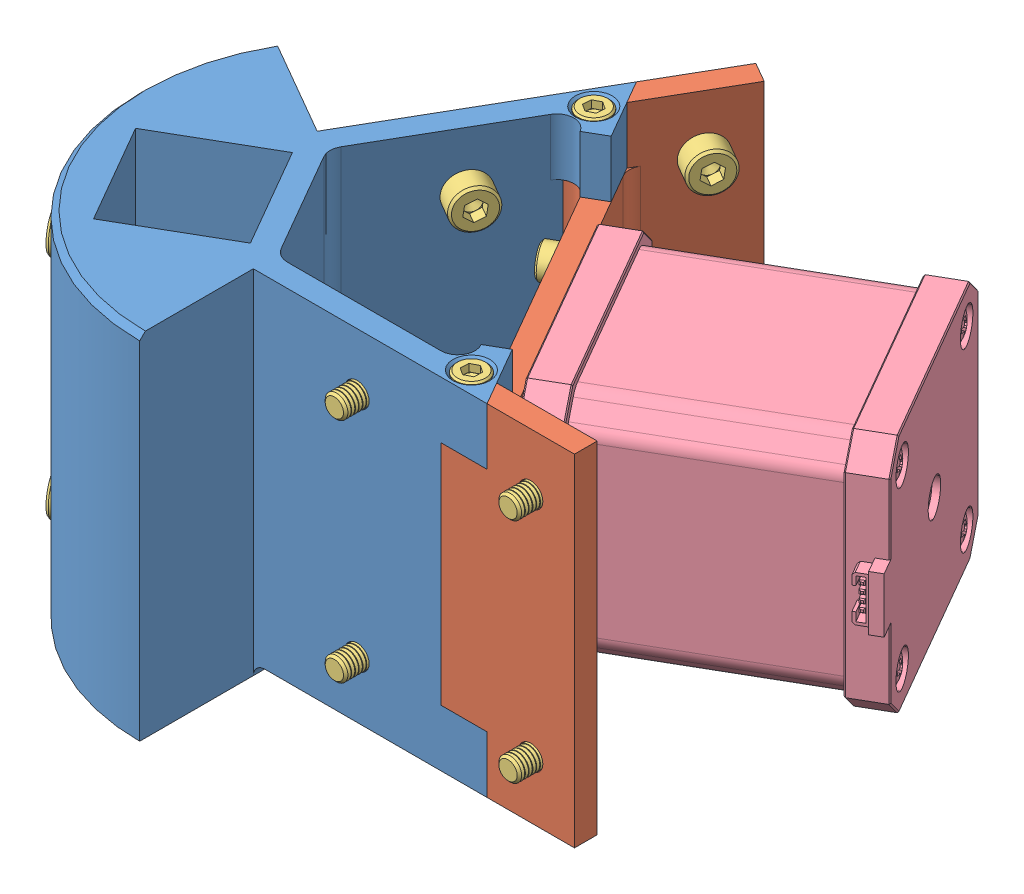
SolidWorks assembly Drive Assembly, configuration Default. Lengths in mm.
Overall size (114.53 65.1 95.5).
23 component instances, 6 part files, 46 mates.
Components (placement in the parent):
- Bottom Corner Support-1: Bottom Corner Support [Default] at origin size (78.83 63 82.18)
- Stepper Mount-1: Stepper Mount [Default] at (0 0 0) x (1 0 0) z (0 0 1) size (55.32 60 75.5)
- socket head cap screw_am-1: socket head cap screw_am [B18.3.1M - 3 x 0.5 x 20 Hex SHCS -- 20SHX] at (53.2197 60 -64.6791) x (0 -1 0) z (-0.546944 0 0.837169) size (23 5.5 5.5)
- socket head cap screw_am-2: socket head cap screw_am [B18.3.1M - 3 x 0.5 x 20 Hex SHCS -- 20SHX] at (53.2197 0 -64.6791) x (0 1 0) z (-0.546944 0 0.837169) size (23 5.5 5.5)
- socket head cap screw_am-3: socket head cap screw_am [B18.3.1M - 3 x 0.5 x 20 Hex SHCS -- 20SHX] at (82.6236 60 -13.75) x (0 -1 0) z (-0.546944 0 0.837169) size (23 5.5 5.5)
- socket head cap screw_am-4: socket head cap screw_am [B18.3.1M - 3 x 0.5 x 20 Hex SHCS -- 20SHX] at (82.6236 0 -13.75) x (0 1 0) z (-0.546944 0 0.837169) size (23 5.5 5.5)
- socket head cap screw_am-5: socket head cap screw_am [B18.3.1M - 4 x 0.7 x 8 Hex SHCS -- 8SHX] at (63.9931 10 -74.8395) x (-0.866026 0 -0.5) z (0.09665 0.98114 -0.167402) size (12 7 7)
- socket head cap screw_am-6: socket head cap screw_am [B18.3.1M - 4 x 0.7 x 8 Hex SHCS -- 8SHX] at (48.7135 50 -48.3742) x (-0.866025 0 -0.5) z (-0.190925 0.924225 0.330691) size (12 7 7)
- socket head cap screw_am-7: socket head cap screw_am [B18.3.1M - 4 x 0.7 x 8 Hex SHCS -- 8SHX] at (48.7135 10 -48.3742) x (-0.866025 0 -0.5) z (-0.190925 0.924225 0.330691) size (12 7 7)
- socket head cap screw_am-8: socket head cap screw_am [B18.3.1M - 4 x 0.7 x 8 Hex SHCS -- 8SHX] at (66.25 10 -18) x (0 0 1) z (-1 0 0) size (12 7 7)
- socket head cap screw_am-9: socket head cap screw_am [B18.3.1M - 4 x 0.7 x 8 Hex SHCS -- 8SHX] at (63.9931 50 -74.8395) x (-0.866026 0 -0.5) z (-0.190925 0.924225 0.330691) size (12 7 7)
- socket head cap screw_am-10: socket head cap screw_am [B18.3.1M - 4 x 0.7 x 8 Hex SHCS -- 8SHX] at (66.25 50 -18) x (0 0 1) z (-1 0 0) size (12 7 7)
- socket head cap screw_am-11: socket head cap screw_am [B18.3.1M - 4 x 0.7 x 8 Hex SHCS -- 8SHX] at (96.8094 10 -18.0001) x (0 0 1) z (-1 0 0) size (12 7 7)
- socket head cap screw_am-12: socket head cap screw_am [B18.3.1M - 4 x 0.7 x 8 Hex SHCS -- 8SHX] at (96.8094 50 -18.0001) x (0 0 1) z (-1 0 0) size (12 7 7)
- socket head cap screw_am-13: socket head cap screw_am [B18.3.1M - 4 x 0.7 x 8 Hex SHCS -- 8SHX] at (14.3627 50 -8.2923) x (0.866025 0 -0.5) z (-0.499976 0.009715 -0.865985) size (12 7 7)
- socket head cap screw_am-14: socket head cap screw_am [B18.3.1M - 4 x 0.7 x 8 Hex SHCS -- 8SHX] at (14.3627 10 -8.2923) x (0.866025 0 -0.5) z (0.5 0 0.866025) size (12 7 7)
- socket head cap screw_am-15: socket head cap screw_am [B18.3.1M - 3 x 0.5 x 8 Hex SHCS -- 8SHX] at (57.357 45.5 -51.013) x (0.866025 0 -0.5) z (0.5 0 0.866025) size (11 5.5 5.5)
- socket head cap screw_am-16: socket head cap screw_am [B18.3.1M - 3 x 0.5 x 8 Hex SHCS -- 8SHX] at (72.857 45.5 -24.1662) x (0.866025 0 -0.5) z (0.5 0 0.866025) size (11 5.5 5.5)
- socket head cap screw_am-17: socket head cap screw_am [B18.3.1M - 3 x 0.5 x 8 Hex SHCS -- 8SHX] at (57.357 14.5 -51.013) x (0.866025 0 -0.5) z (0.5 0 0.866025) size (11 5.5 5.5)
- socket head cap screw_am-18: socket head cap screw_am [B18.3.1M - 3 x 0.5 x 8 Hex SHCS -- 8SHX] at (72.857 14.5 -24.1662) x (0.866025 0 -0.5) z (0.5 0 0.866025) size (11 5.5 5.5)
- Drive Stepper-1: Drive Stepper [Défaut] at (69.4371 30 -40.0896) x (-0.5 0 -0.866025) z (0.866025 0 -0.5) size (45.3 42.3 72)
- Drive Pulley-1: Drive Pulley [Конфигурация1] at (64.241 30 -37.0896) x (-0.866025 0 0.5) z (-0.435421 -0.491563 -0.754171) size (16 16 16)
- Rubber Foot-1: Rubber Foot [Default] at (28.7942 -2.5 -16.6244) x (1 0 0) z (0 0 -1) size (15.2 2.6 15.2)
Mates (geometry in assembly coordinates):
- Concentric1: concentric: cylinder of Bottom Corner Support-1 through (53.2197 0 -64.6791) axis (0 1 0) radius 1.6; cylinder of Stepper Mount-1 through (53.2197 0 -64.6791) axis (0 1 0) radius 1.25
- Concentric2: concentric: cylinder of Bottom Corner Support-1 through (82.6236 0 -13.75) axis (0 1 0) radius 1.6; cylinder of Stepper Mount-1 through (82.6236 0 -13.7501) axis (0 1 0) radius 1.25
- Coincident1: coincident: plane of Bottom Corner Support-1 through (53.2197 10 -58.1791) normal (0 1 0); plane of Stepper Mount-1 through (58.9931 10 -68.1792) normal (0 -1 0)
- Concentric3: concentric: cylinder of Bottom Corner Support-1 through (53.2197 57 -64.6791) axis (0 1 0) radius 2.75; cylinder of socket head cap screw_am-1 through (53.2197 91.75 -64.6791) axis (0 1 0) radius 2.75
- Coincident2: coincident: plane of Bottom Corner Support-1 through (53.2197 57 -64.6791) normal (0 1 0); plane of socket head cap screw_am-1 through (55.5219 57 -63.1751) normal (0 -1 0)
- Concentric4: concentric: cylinder of Bottom Corner Support-1 through (53.2197 3 -64.6791) axis (0 -1 0) radius 2.75; cylinder of socket head cap screw_am-2 through (53.2197 -31.75 -64.6791) axis (0 -1 0) radius 2.75
- Coincident3: coincident: plane of Bottom Corner Support-1 through (53.2197 3 -64.6791) normal (0 -1 0); plane of socket head cap screw_am-2 through (50.9174 3 -66.1832) normal (0 1 0)
- Concentric5: concentric: cylinder of Bottom Corner Support-1 through (82.6236 57 -13.75) axis (0 1 0) radius 2.75; cylinder of socket head cap screw_am-3 through (82.6236 91.75 -13.75) axis (0 1 0) radius 2.75
- Coincident4: coincident: plane of Bottom Corner Support-1 through (82.6236 57 -13.75) normal (0 1 0); plane of socket head cap screw_am-3 through (84.9258 57 -12.2459) normal (0 -1 0)
- Concentric6: concentric: cylinder of Bottom Corner Support-1 through (82.6236 3 -13.75) axis (0 -1 0) radius 2.75; cylinder of socket head cap screw_am-4 through (82.6236 -31.75 -13.75) axis (0 -1 0) radius 2.75
- Coincident5: coincident: plane of Bottom Corner Support-1 through (82.6236 3 -13.75) normal (0 -1 0); plane of socket head cap screw_am-4 through (80.3214 3 -15.2541) normal (0 1 0)
- Concentric7: concentric: cylinder of Bottom Corner Support-1 through (50.4545 50 -47.369) axis (-0.866025 0 -0.5) radius 2.125; cylinder of socket head cap screw_am-6 through (76.2098 50 -32.4992) axis (0.866025 0 0.5) radius 3.5
- Concentric8: concentric: cylinder of Stepper Mount-1 through (65.7342 50 -73.8342) axis (-0.866026 0 -0.5) radius 2.125; cylinder of socket head cap screw_am-9 through (91.4894 50 -58.9645) axis (0.866026 0 0.5) radius 3.5
- Concentric9: concentric: cylinder of Bottom Corner Support-1 through (50.4545 10 -47.369) axis (-0.866025 0 -0.5) radius 2.125; cylinder of socket head cap screw_am-7 through (76.2098 10 -32.4992) axis (0.866025 0 0.5) radius 3.5
- Concentric10: concentric: cylinder of Stepper Mount-1 through (65.7342 10 -73.8342) axis (-0.866026 0 -0.5) radius 2.125; cylinder of socket head cap screw_am-5 through (91.4894 10 -58.9645) axis (0.866026 0 0.5) radius 3.5
- Coincident6: coincident: plane of Stepper Mount-1 through (56.395 60 -69.6792) normal (0.866026 0 0.5); plane of socket head cap screw_am-5 through (58.812 10.6765 -73.8655) normal (-0.866026 0 -0.5)
- Coincident7: coincident: plane of Stepper Mount-1 through (56.395 60 -69.6792) normal (0.866026 0 0.5); plane of socket head cap screw_am-9 through (58.9116 48.6635 -74.038) normal (-0.866026 0 -0.5)
- Coincident8: coincident: plane of Bottom Corner Support-1 through (53.2197 60 -64.1791) normal (0.866025 0 0.5); plane of socket head cap screw_am-6 through (43.632 48.6635 -47.5728) normal (-0.866025 0 -0.5)
- Coincident9: coincident: plane of Bottom Corner Support-1 through (53.2197 60 -64.1791) normal (0.866025 0 0.5); plane of socket head cap screw_am-7 through (43.632 8.6635 -47.5728) normal (-0.866025 0 -0.5)
- Concentric11: concentric: cylinder of Bottom Corner Support-1 through (66.25 10 -20.0104) axis (0 0 1) radius 2.125; cylinder of socket head cap screw_am-8 through (66.25 10 -49.75) axis (0 0 -1) radius 3.5
- Concentric12: concentric: cylinder of Bottom Corner Support-1 through (66.25 50 -20.0104) axis (0 0 1) radius 2.125; cylinder of socket head cap screw_am-10 through (66.25 50 -49.75) axis (0 0 -1) radius 3.5
- Concentric13: concentric: cylinder of Stepper Mount-1 through (96.8094 10 -20.0105) axis (0 0 1) radius 2.125; cylinder of socket head cap screw_am-11 through (96.8094 10 -49.7501) axis (0 0 -1) radius 3.5
- Concentric14: concentric: cylinder of Stepper Mount-1 through (96.8094 50 -20.0105) axis (0 0 1) radius 2.125; cylinder of socket head cap screw_am-12 through (96.8094 50 -49.7501) axis (0 0 -1) radius 3.5
- Coincident10: coincident: plane of Stepper Mount-1 through (104.5 60 -14.0001) normal (0 0 -1); plane of socket head cap screw_am-12 through (96.8094 53.5 -14.0001) normal (0 0 1)
- Coincident11: coincident: plane of Stepper Mount-1 through (104.5 60 -14.0001) normal (0 0 -1); plane of socket head cap screw_am-11 through (96.8094 13.5 -14.0001) normal (0 0 1)
- Coincident12: coincident: plane of Bottom Corner Support-1 through (49.9808 60 -14) normal (0 0 -1); plane of socket head cap screw_am-8 through (66.25 13.5 -14) normal (0 0 1)
- Coincident13: coincident: plane of Bottom Corner Support-1 through (49.9808 60 -14) normal (0 0 -1); plane of socket head cap screw_am-10 through (66.25 53.5 -14) normal (0 0 1)
- Concentric15: concentric: cylinder of Bottom Corner Support-1 through (17.8268 50 -10.2923) axis (-0.866025 0 0.5) radius 3.65; cylinder of socket head cap screw_am-13 through (-13.1336 50 7.5827) axis (-0.866025 0 0.5) radius 3.5
- Coincident14: coincident: plane of Bottom Corner Support-1 through (17.8268 50 -10.2923) normal (-0.866025 0 0.5); plane of socket head cap screw_am-13 through (17.8098 46.5002 -10.3218) normal (0.866025 0 -0.5)
- Concentric16: concentric: cylinder of Bottom Corner Support-1 through (17.8268 10 -10.2923) axis (-0.866025 0 0.5) radius 3.65; cylinder of socket head cap screw_am-14 through (-13.1336 10 7.5827) axis (-0.866025 0 0.5) radius 3.5
- Coincident15: coincident: plane of Bottom Corner Support-1 through (17.8268 10 -10.2923) normal (-0.866025 0 0.5); plane of socket head cap screw_am-14 through (17.8268 13.5 -10.2923) normal (0.866025 0 -0.5)
- Concentric17: concentric: cylinder of Stepper Mount-1 through (23.2128 45.5 -31.2998) axis (0.866025 0 -0.5) radius 1.6; cylinder of socket head cap screw_am-15 through (29.8607 45.5 -35.138) axis (-0.866025 0 0.5) radius 2.75
- Concentric18: concentric: cylinder of Stepper Mount-1 through (38.7128 45.5 -4.453) axis (0.866025 0 -0.5) radius 1.6; cylinder of socket head cap screw_am-16 through (45.3607 45.5 -8.2912) axis (-0.866025 0 0.5) radius 2.75
- Concentric19: concentric: cylinder of Stepper Mount-1 through (23.2128 14.5 -31.2998) axis (0.866025 0 -0.5) radius 1.6; cylinder of socket head cap screw_am-17 through (29.8607 14.5 -35.138) axis (-0.866025 0 0.5) radius 2.75
- Concentric20: concentric: cylinder of Stepper Mount-1 through (38.7128 14.5 -4.453) axis (0.866025 0 -0.5) radius 1.6; cylinder of socket head cap screw_am-18 through (45.3607 14.5 -8.2912) axis (-0.866025 0 0.5) radius 2.75
- Coincident16: coincident: plane of Stepper Mount-1 through (53.2196 60 -64.1792) normal (-0.866025 0 0.5); plane of socket head cap screw_am-18 through (75.4551 17.25 -25.6662) normal (0.866025 0 -0.5)
- Coincident17: coincident: plane of Stepper Mount-1 through (53.2196 60 -64.1792) normal (-0.866025 0 0.5); plane of socket head cap screw_am-16 through (75.4551 48.25 -25.6662) normal (0.866025 0 -0.5)
- Coincident18: coincident: plane of Stepper Mount-1 through (53.2196 60 -64.1792) normal (-0.866025 0 0.5); plane of socket head cap screw_am-17 through (59.9551 17.25 -52.513) normal (0.866025 0 -0.5)
- Coincident19: coincident: plane of Stepper Mount-1 through (53.2196 60 -64.1792) normal (-0.866025 0 0.5); plane of socket head cap screw_am-15 through (59.9551 48.25 -52.513) normal (0.866025 0 -0.5)
- Concentric21: concentric: cylinder of socket head cap screw_am-16 through (45.3607 45.5 -8.2912) axis (-0.866025 0 0.5) radius 2.75; cylinder of Drive Stepper-1 through (132.6128 45.5 -58.6663) axis (-0.866025 0 0.5) radius 1.5
- Concentric22: concentric: cylinder of socket head cap screw_am-17 through (29.8607 14.5 -35.138) axis (-0.866025 0 0.5) radius 2.75; cylinder of Drive Stepper-1 through (117.1127 14.5 -85.513) axis (-0.866025 0 0.5) radius 1.5
- Coincident20: coincident: plane of Stepper Mount-1 through (85.9434 60 -15.5001) normal (0.866025 0 -0.5); plane of Drive Stepper-1 through (71.1692 30 -41.0896) normal (-0.866025 0 0.5)
- Concentric23: concentric: cylinder of Drive Stepper-1 through (50.3846 30 -29.0896) axis (0.866025 0 -0.5) radius 2.5; cylinder of Drive Pulley-1 through (64.241 30 -37.0896) axis (-0.866025 0 0.5) radius 4
- Coincident21: coincident: plane of Drive Stepper-1 through (50.3846 30 -29.0896) normal (-0.866025 0 0.5); plane of Drive Pulley-1 through (50.3846 30 -29.0896) normal (-0.866025 0 0.5)
- Coincident22: coincident: plane of Bottom Corner Support-1 through (28.7942 -2.5 -16.6244) normal (0 -1 0); plane of Rubber Foot-1 through (28.7942 -2.5 -16.6244) normal (0 1 0)
- Concentric24: concentric: cylinder of Bottom Corner Support-1 through (28.7942 -2.5 -16.6244) axis (0 -1 0) radius 7.75; cylinder of Rubber Foot-1 through (28.7942 -5.1 -16.6244) axis (0 1 0) radius 7.6
